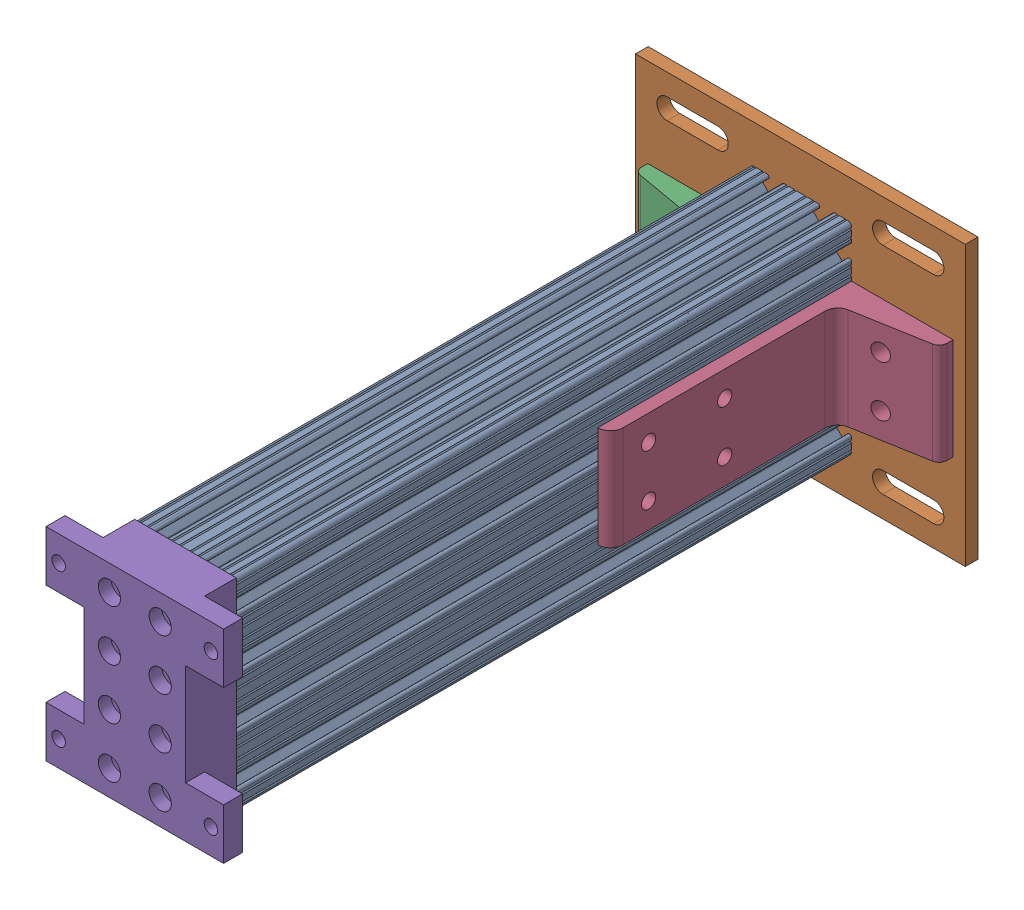
SolidWorks assembly Mirrorbreadboard support leg assembly, configuration Default. Lengths in mm.
Overall size (165.1 139.7 339.72).
6 component instances, 4 part files, 6 mates.
Components (placement in the parent):
- Mirror8020-2040 leg for breadboard support-1: Mirror8020-2040 leg for breadboard support [Default] at (-48.9055 -77.0614 -78.1612) size (50.8 101.6 307.98)
- Mirror8020-2387-DEFAULT-1: Mirror8020-2387-DEFAULT [Default] at (-34.9863 -22.6888 -91.8816) x (0 1 0) z (1 0 0) size (139.7 133.35 165.1)
  - Mirror8020-2387-DEFAULT_238708-1: Mirror8020-2387-DEFAULT_238708 [Default] at (-67.1549 7.3704 -27.8119) size (139.7 6.35 165.1)
  - Mirror8020-2387-DEFAULT_238509-1: Mirror8020-2387-DEFAULT_238509 [Default] at (9.1264 0.0214 -49.7635) x (0 0 -1) z (1 0 0) size (50.8 127 50.8)
  - Mirror8020-2387-DEFAULT_238509-2: Mirror8020-2387-DEFAULT_238509 [Default] at (-41.6736 0.0214 46.9187) x (0 0 1) z (-1 0 0) size (50.8 127 50.8)
- Mirrorbreadboard support leg top bracket-1: Mirrorbreadboard support leg top bracket [Default] at (-61.6055 -89.7614 229.8138) x (0 1 0) z (1 0 0) size (101.6 25.4 88.9)
Mates (geometry in assembly coordinates):
- Coincident1: coincident anti-aligned: plane of Mirror8020-2040 leg for breadboard support-1 through (-61.6055 -36.3198 -78.1612) normal (0 0 -1); plane of Mirror8020-2387-DEFAULT-1/Mirror8020-2387-DEFAULT_238708-1 through (-36.4088 -207.3239 -78.1612) normal (0 0 1)
- Coincident2: coincident anti-aligned: plane of Mirror8020-2040 leg for breadboard support-1 through (-10.8056 -41.095 229.8138) normal (1 0 0); plane of Mirror8020-2387-DEFAULT-1/Mirror8020-2387-DEFAULT_238509-2 through (-10.8056 -13.5624 -150.9329) normal (-1 0 0)
- Distance1: distance = 19.05 mm aligned: plane of Mirror8020-2387-DEFAULT-1/Mirror8020-2387-DEFAULT_238708-1 through (-36.4088 -108.8114 -78.1612) normal (0 -1 0); plane of Mirror8020-2040 leg for breadboard support-1 through (-38.3391 -89.7614 229.8138) normal (0 -1 0)
- Coincident3: coincident anti-aligned: plane of Mirror8020-2040 leg for breadboard support-1 through (-61.6055 -36.3198 229.8138) normal (0 0 1); plane of Mirrorbreadboard support leg top bracket-1 through (-10.8055 -89.7614 229.8138) normal (0 0 -1)
- Concentric1: concentric anti-aligned: circle of Mirror8020-2040 leg for breadboard support-1; circle of Mirrorbreadboard support leg top bracket-1
- Concentric2: concentric anti-aligned: circle of Mirror8020-2040 leg for breadboard support-1; circle of Mirrorbreadboard support leg top bracket-1
